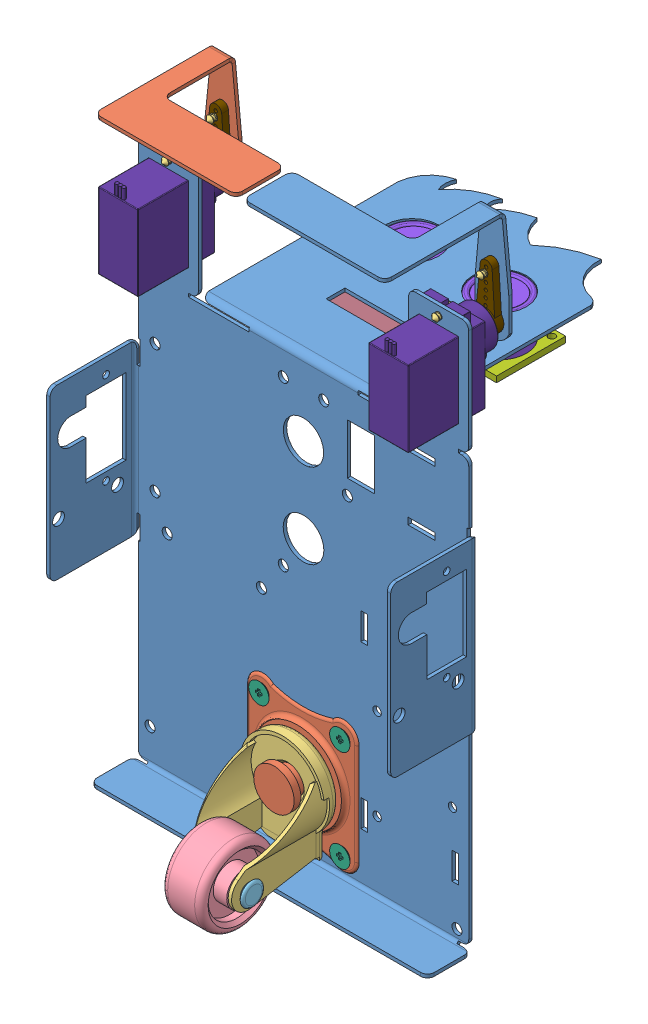
SolidWorks assembly Ensamblaje16, configuration Predeterminado. Lengths in mm.
Overall size (102 183.65 106.61).
59 component instances, 22 part files, 12 mates.
Components (placement in the parent):
- DYOR_OLED_MetalSheet_Pusher-1: DYOR_OLED_MetalSheet_Pusher [Predeterminado] at (90.3983 -137.9363 139.7994) size (102 161.68 94.67)
- CA-1: CA [Predeterminado] at (0.0001 -0.5 0) size (33 45.94 43.84)
  - Caster Wheel-1: Caster Wheel [Default] at (197.1109 -294.8334 184.5177) x (0 1 0) z (-1 0 0) size (45.94 37.15 33)
    - caster holder-1: caster holder [Default] at (-24.0751 44.7184 29.5137) x (1 0 0) z (0 0 -1) size (39 8.84 33)
    - holder-1: holder [Default] at (-1.5751 42.9484 46.0137) x (0 0 1) z (1 0 0) size (25 28.07 31.31)
    - caster wheel-1: caster wheel [Default] at (-15.6961 19.9484 46.0137) x (0.997275 0.073773 0) z (0 0 1) size (23 23 14)
    - Part4-1: Part4 [Default] at (-15.6961 19.9484 55.0137) x (-0.978448 0.206495 0) z (0 0 -1) size (7 7 20)
  - M4x8 SelfTap Screw-1: M4x8 SelfTap Screw [Predeterminado] at (139.0972 -281.4086 141.0494) size (6 6 8)
  - M4x8 SelfTap Screw-2: M4x8 SelfTap Screw [Predeterminado] at (163.0972 -281.4086 141.0494) size (6 6 8)
  - M4x8 SelfTap Screw-3: M4x8 SelfTap Screw [Predeterminado] at (139.0972 -311.4086 141.0494) size (6 6 8)
  - M4x8 SelfTap Screw-4: M4x8 SelfTap Screw [Predeterminado] at (163.0972 -311.4086 141.0494) size (6 6 8)
- HC-SR04 Ping Sensor-1: HC-SR04 Ping Sensor [Default] at (150.9373 -203.2073 94.6556) x (0 0 -1) z (0 1 0) size (25.18 45 18.07)
  - PCB-1: PCB [Default] at origin size (20.5 45 1.75)
  - Transducer-1: Transducer [Default] at (0 -13.16 13.25) x (1 0 0) z (0 -1 0) size (15.88 12 15.88)
  - Transducer-2: Transducer [Default] at (0 12.34 13.25) x (1 0 0) z (0 -1 0) size (15.88 12 15.88)
  - 3 Pin Header 90 Degree-1: 3 Pin Header 90 Degree [Default] at (8.4275 0 -1.25) x (-1 0 0) z (0 -1 0) size (8 7.82 10)
  - 14 Pin SMT-1: 14 Pin SMT [Default] at (-0.35 -18.5 -0.85) x (0 -1 0) z (1 0 0) size (6 1.6 8.8)
  - 14 Pin SMT-2: 14 Pin SMT [Default] at (0 -0.3826 -0.85) x (1 0 0) z (0 1 0) size (6 1.6 8.8)
  - 14 Pin SMT-3: 14 Pin SMT [Default] at (0 17.5274 -0.85) x (1 0 0) z (0 1 0) size (6 1.6 8.8)
  - Cap1 SMT-1: Cap1 SMT [Default] at (-1.755 7.4774 -0.9689) x (0 1 0) z (-1 0 0) size (4.5 1.84 1.75)
  - Cap1 SMT-2: Cap1 SMT [Default] at (6.835 7.4774 -0.9689) x (0 1 0) z (-1 0 0) size (4.5 1.84 1.75)
  - Cap1 SMT-3: Cap1 SMT [Default] at (-6.835 7.4774 -0.9689) x (0 1 0) z (-1 0 0) size (4.5 1.84 1.75)
  - Cap1 SMT-4: Cap1 SMT [Default] at (4.295 7.4774 -0.9689) x (0 1 0) z (-1 0 0) size (4.5 1.84 1.75)
  - Cap1 SMT-5: Cap1 SMT [Default] at (1.755 7.4774 -0.9689) x (0 1 0) z (-1 0 0) size (4.5 1.84 1.75)
  - Cap1 SMT-6: Cap1 SMT [Default] at (-4.295 7.4774 -0.9689) x (0 1 0) z (-1 0 0) size (4.5 1.84 1.75)
  - HC-SR04 Crystal-1: HC-SR04 Crystal [Default] at (-8.3 0 1.75) x (0 -1 0) z (0 0 1) size (10 3.5 2.7)
- OLED_0.91_128x32-1: OLED_0.91_128x32 [Predeterminado] at (152.4982 -192.9673 120.4515) x (1 0 0) z (0 1 0) size (38.3 12.1 11.46)
  - OLED_0.91_128x32.stp-1: OLED_0.91_128x32.stp [Predeterminado] at origin size (38.3 12.1 11.46)
    - OLED_0.91_128x32.stp-1: OLED_0.91_128x32.stp [Predeterminado] at origin size (38.3 12.1 2.57)
    - Pin Header 4 x 1 TH 2.54mm Pitch.stp-1: Pin Header 4 x 1 TH 2.54mm Pitch.stp [Predeterminado] at (-17.55 -3.81 -2.6) size (2.54 10.16 11.43)
    - RESC-0603.stp-1: RESC-0603.stp [Predeterminado] at (4.3 -5.3 0) x (1 0 0) z (0 0 -1) size (1.7 0.9 0.55)
    - RESC-0603.stp-2: RESC-0603.stp [Predeterminado] at (4.3 -3.8 0) x (1 0 0) z (0 0 -1) size (1.7 0.9 0.55)
    - RESC-0603.stp-3: RESC-0603.stp [Predeterminado] at (4.3 -2.3 0) x (1 0 0) z (0 0 -1) size (1.7 0.9 0.55)
    - RESC-0603.stp-4: RESC-0603.stp [Predeterminado] at (4.3 -0.8 0) x (1 0 0) z (0 0 -1) size (1.7 0.9 0.55)
    - RESC-0603.stp-5: RESC-0603.stp [Predeterminado] at (4.3 0.7 0) x (1 0 0) z (0 0 -1) size (1.7 0.9 0.55)
    - RESC-0603.stp-6: RESC-0603.stp [Predeterminado] at (4.3 2.2 0) x (1 0 0) z (0 0 -1) size (1.7 0.9 0.55)
    - RESC-0603.stp-7: RESC-0603.stp [Predeterminado] at (4.3 3.7 0) x (1 0 0) z (0 0 -1) size (1.7 0.9 0.55)
    - RESC-0603.stp-8: RESC-0603.stp [Predeterminado] at (4.3 5.2 0) x (1 0 0) z (0 0 -1) size (1.7 0.9 0.55)
    - RESC-0603.stp-9: RESC-0603.stp [Predeterminado] at (-1.4 -3.06 0) x (1 0 0) z (0 0 -1) size (1.7 0.9 0.55)
    - RESC-0603.stp-10: RESC-0603.stp [Predeterminado] at (-1.4 -1.56 0) x (1 0 0) z (0 0 -1) size (1.7 0.9 0.55)
    - RESC-0603.stp-11: RESC-0603.stp [Predeterminado] at (-1.4 -0.06 0) x (1 0 0) z (0 0 -1) size (1.7 0.9 0.55)
    - RESC-0603.stp-12: RESC-0603.stp [Predeterminado] at (-1.4 1.44 0) x (1 0 0) z (0 0 -1) size (1.7 0.9 0.55)
    - RESC-0603.stp-13: RESC-0603.stp [Predeterminado] at (-1.4 2.94 0) x (1 0 0) z (0 0 -1) size (1.7 0.9 0.55)
    - 2SD0601A.stp-1: 2SD0601A.stp [Predeterminado] at (-9.8 -1.3 -0.08) x (1 0 0) z (0 1 0) size (2.76 1.18 2.9)
- PU-1: PU [Predeterminado] at (-16.3265 4.6781 -1.0225) size (91.94 49.57 37.38)
  - sg90-1: sg90 [Default] at (201.5956 -166.7354 155.7219) x (0 -1 0) z (1 0 0) size (31.9 29.9 11.8)
  - sg90-2: sg90 [Default] at (121.452 -166.7354 155.7219) x (0 -1 0) z (1 0 0) size (31.9 29.9 11.8)
  - SG90 plastic Horn-1: SG90 plastic Horn [Default] at (127.352 -172.6354 127.0219) x (0.017141 0.999853 0) z (-0.999853 0.017141 0) size (19.4 4 7.07)
  - SG90 plastic Horn-2: SG90 plastic Horn [Default] at (207.4956 -172.6354 127.0219) x (0.020276 0.999794 0) z (-0.999794 0.020276 0) size (19.4 4 7.07)
  - Pusher_left-1: Pusher_left [Predeterminado] at (252.6438 -158.8738 124.0219) x (-1 0 0) z (0 0 -1) size (44 33.65 35.77)
  - Pusher_right-1: Pusher_right [Predeterminado] at (82.2037 -158.8738 125.0219) size (44 33.65 35.77)
  - M2x6 SelfTap Screw-1: M2x6 SelfTap Screw [Predeterminado] at (207.4956 -164.3354 136.8219) x (-0.923728 -0.383049 0) z (0 0 -1) size (3.4 3.28 6)
  - M2x6 SelfTap Screw-2: M2x6 SelfTap Screw [Predeterminado] at (207.4956 -191.6354 136.3219) x (-0.923728 -0.383049 0) z (0 0 -1) size (3.4 3.28 6)
  - M2x6 SelfTap Screw-3: M2x6 SelfTap Screw [Predeterminado] at (127.352 -164.3354 136.8219) x (-0.993348 0.115149 0) z (0 0 -1) size (3.4 3.28 6)
  - M2x6 SelfTap Screw-4: M2x6 SelfTap Screw [Predeterminado] at (127.352 -191.6354 136.8219) x (-0.923728 -0.383049 0) z (0 0 -1) size (3.4 3.28 6)
  - (M2_3_mm)_90116A007_METRIC 316 SS PAN HEAD PHILLIPS MACHINE SCREW-1: (M2_3_mm)_90116A007_METRIC 316 SS PAN HEAD PHILLIPS MACHINE SCREW [90116A007] at (127.352 -172.6354 127.0219) x (-0.923728 -0.383049 0) z (0 0 -1) size (4 4 4.68)
  - (M2_3_mm)_90116A007_METRIC 316 SS PAN HEAD PHILLIPS MACHINE SCREW-2: (M2_3_mm)_90116A007_METRIC 316 SS PAN HEAD PHILLIPS MACHINE SCREW [90116A007] at (207.4956 -172.6354 127.0219) x (-0.923728 -0.383049 0) z (0 0 -1) size (4 4 4.68)
  - M2x6 SelfTap Screw-5: M2x6 SelfTap Screw [Predeterminado] at (127.352 -160.1354 123.5219) x (-0.923728 -0.383049 0) z (0 0 -1) size (3.4 3.28 6)
  - M2x6 SelfTap Screw-6: M2x6 SelfTap Screw [Predeterminado] at (207.4956 -160.1354 123.5219) x (-0.923728 -0.383049 0) z (0 0 -1) size (3.4 3.28 6)
Mates (geometry in assembly coordinates):
- Coincidente578: coincident: plane of DYOR_OLED_MetalSheet_Pusher-1 through (122.9255 -188.9573 139.7994) normal (0 0 1); plane of CA-1/Caster Wheel-1/caster holder-1 through (151.0973 -252.1104 139.7994) normal (0 0 -1)
- Concéntrica334: concentric: circle of DYOR_OLED_MetalSheet_Pusher-1; circle of CA-1/M4x8 SelfTap Screw-2
- Concéntrica335: concentric: circle of DYOR_OLED_MetalSheet_Pusher-1; circle of CA-1/M4x8 SelfTap Screw-4
- Concéntrica336: concentric: circle of DYOR_OLED_MetalSheet_Pusher-1; circle of HC-SR04 Ping Sensor-1/Transducer-1
- Paralelo106: parallel: plane of DYOR_OLED_MetalSheet_Pusher-1 through (122.9255 -188.9573 138.7994) normal (0 0 -1); plane of HC-SR04 Ping Sensor-1/PCB-1 through (128.4373 -201.4573 104.9056) normal (0 0 1)
- Coincidente580: coincident: plane of DYOR_OLED_MetalSheet_Pusher-1 through (122.9255 -189.4573 137.6556) normal (0 1 0); plane of HC-SR04 Ping Sensor-1/Transducer-1 through (164.0973 -189.4573 86.7156) normal (0 1 0)
- Coincidente581: coincident: plane of DYOR_OLED_MetalSheet_Pusher-1 through (122.9255 -190.4573 137.6556) normal (0 -1 0); plane of OLED_0.91_128x32-1/OLED_0.91_128x32.stp-1/OLED_0.91_128x32.stp-1 through (151.2982 -190.4573 120.4515) normal (0 1 0)
- Distancia70: distance = 2.1 mm: plane of OLED_0.91_128x32-1/OLED_0.91_128x32.stp-1/OLED_0.91_128x32.stp-1 through (168.2482 -191.8173 114.6515) normal (0 0 -1); plane of DYOR_OLED_MetalSheet_Pusher-1 through (162.7322 -190.4573 116.7515) normal (0 0 1)
- Distancia71: distance = 2.1 mm: plane of OLED_0.91_128x32-1/OLED_0.91_128x32.stp-1/OLED_0.91_128x32.stp-1 through (138.2482 -191.8173 114.6515) normal (-1 0 0); plane of DYOR_OLED_MetalSheet_Pusher-1 through (140.3482 -190.4573 116.7515) normal (1 0 0)
- Coincidente584: coincident: plane of DYOR_OLED_MetalSheet_Pusher-1 through (122.9255 -188.9573 138.7994) normal (0 0 -1); plane of PU-1/sg90-1 through (197.0691 -189.2573 138.7994) normal (0 0 1)
- Concéntrica337: concentric: circle of DYOR_OLED_MetalSheet_Pusher-1; circle of PU-1/M2x6 SelfTap Screw-2
- Concéntrica338: concentric: circle of DYOR_OLED_MetalSheet_Pusher-1; circle of PU-1/M2x6 SelfTap Screw-1
